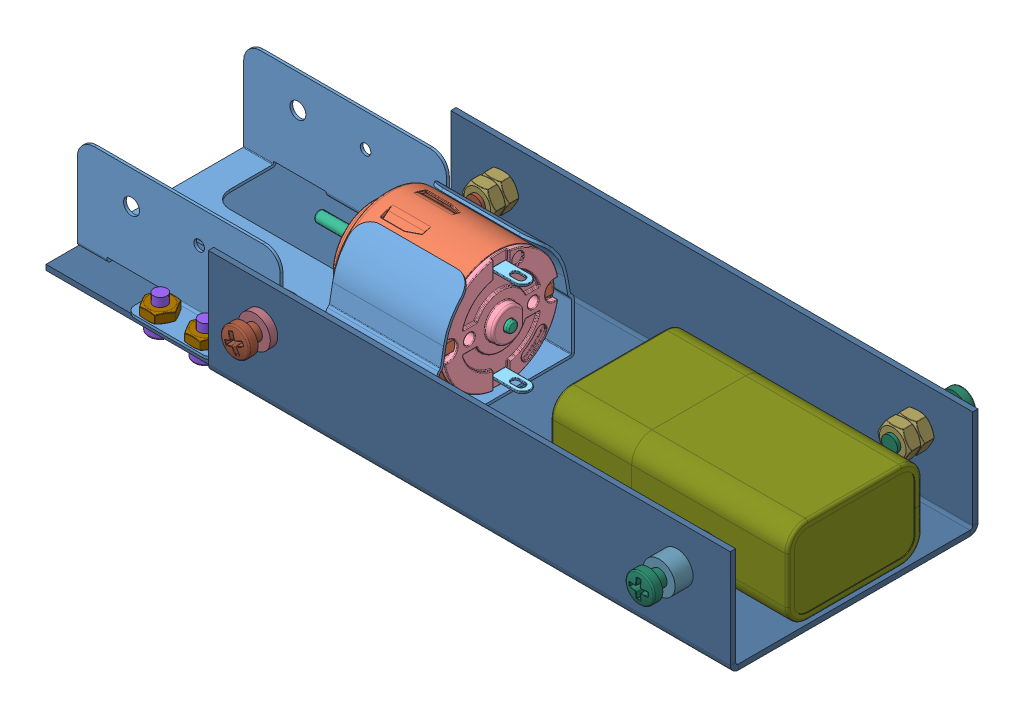
SolidWorks assembly Walking_robot_(fixed_body), configuration Default. Lengths in mm.
Overall size (130 25.8 61.22).
37 component instances, 16 part files, 0 mates.
Components (placement in the parent):
- ELENCO GEAR BOX 01-1: ELENCO GEAR BOX 01 [Default] at origin size (64.7 22.22 44.45)
- ELENCO DC Motor 3V-1: ELENCO DC Motor 3V [Predeterminado] at (28.3843 11.811 0) x (0 0 1) z (-1 0 0) size (22.78 22.72 39.63)
  - ELENCO MOTOR HOUSING 01-1: ELENCO MOTOR HOUSING 01 [Predeterminado] at (0 0 24.0663) size (21.61 21.6 25.37)
  - ELENCO FRONT BUSHING-1: ELENCO FRONT BUSHING [Predeterminado] at (0 0 28.0103) x (0.939098 -0.34365 0) z (0 0 1) size (4.5 4.5 0.5)
  - ELENCO MOTOR BACK 01-1: ELENCO MOTOR BACK 01 [Predeterminado] at (0 0 4.731) x (-1 0 0) z (0 0 -1) size (21.23 21.59 3.58)
  - Terminal3V-1: Terminal3V [Predeterminado] at (0 -8.7 5.331) x (1 0 0) z (0 1 0) size (2.9 8 0.4)
  - Terminal3V-2: Terminal3V [Predeterminado] at (0 8.7 5.331) x (1 0 0) z (0 1 0) size (2.9 8 0.4)
  - ELENCO ARMATURE 01-1: ELENCO ARMATURE 01 [Predeterminado] at (0 0 36.9603) x (-0.892263 0.451515 0) z (0 0 1) size (17 16.86 36.46)
  - Enrolamento3V-1: Enrolamento3V [Predeterminado] at (2.0691 4.0889 14.4603) x (0.892263 -0.451515 0) z (0 0 1) size (7 3 16)
  - Enrolamento3V-2: Enrolamento3V [Predeterminado] at (-4.5756 -0.2525 14.4603) x (-0.055108 0.99848 0) z (0 0 1) size (7 3 16)
  - Enrolamento3V-3: Enrolamento3V [Predeterminado] at (2.5065 -3.8363 14.4603) x (-0.837155 -0.546965 0) z (0 0 1) size (7 3 16)
- Walking_robot_(bolt_2_5x5)-1: Walking_robot_(bolt_2_5x5) [Default] at (-18.85 -1 19.55) x (0 -1 0) z (-0.551694 0 0.834047) size (6.57 4.4 4.4)
- Walking_robot_(nut_2_5)-1: Walking_robot_(nut_2_5) [Default] at (-18.85 2.368 19.55) x (0.999996 0 -0.002907) z (0 -1 0) size (5.74 5.33 2.2)
- Walking_robot_(bolt_2_5x5)-2: Walking_robot_(bolt_2_5x5) [Default] at (-18.85 -1 -19.55) x (0 -1 0) z (-0.551694 0 0.834047) size (6.57 4.4 4.4)
- Walking_robot_(bolt_2_5x5)-3: Walking_robot_(bolt_2_5x5) [Default] at (-10.35 -1 19.55) x (0 -1 0) z (-0.551694 0 0.834047) size (6.57 4.4 4.4)
- Walking_robot_(bolt_2_5x5)-4: Walking_robot_(bolt_2_5x5) [Default] at (-10.35 -1 -19.55) x (0 -1 0) z (-0.551694 0 0.834047) size (6.57 4.4 4.4)
- Walking_robot_(nut_2_5)-2: Walking_robot_(nut_2_5) [Default] at (-18.85 2.368 -19.55) x (0.999996 0 -0.002907) z (0 -1 0) size (5.74 5.33 2.2)
- Walking_robot_(nut_2_5)-3: Walking_robot_(nut_2_5) [Default] at (-10.35 2.368 19.55) x (0.999996 0 -0.002907) z (0 -1 0) size (5.74 5.33 2.2)
- Walking_robot_(nut_2_5)-4: Walking_robot_(nut_2_5) [Default] at (-10.35 2.368 -19.55) x (0.999996 0 -0.002907) z (0 -1 0) size (5.74 5.33 2.2)
- Walking_robot_(main_body)-1: Walking_robot_(main_body) [Default] at (42.9 -1 0) x (0 0 1) z (-1 0 0) size (46.5 20 130)
- Walking_robot_(bolt_3x10)-1: Walking_robot_(bolt_3x10) [Default] at (3.9 11.5 -26.63) x (0 0 -1) z (1 0 0) size (11.98 5.4 5.4)
- Walking_robot_(nut_3)-1: Walking_robot_(nut_3) [Default] at (3.9 11.5 -19.75) size (6.75 5.87 2.78)
- Walking_robot_(bolt_3x10)-2: Walking_robot_(bolt_3x10) [Default] at (3.9 11.5 26.63) x (0 0 1) z (-0.923728 -0.383049 0) size (11.98 5.4 5.4)
- Walking_robot_(nut_3)-7: Walking_robot_(nut_3) [Default] at (3.9 11.5 -22.25) size (6.75 5.87 2.78)
- Walking_robot_(nut_3)-9: Walking_robot_(nut_3) [Default] at (3.9 11.5 19.75) size (6.75 5.87 2.78)
- Walking_robot_(nut_3)-11: Walking_robot_(nut_3) [Default] at (3.9 11.5 17.25) size (6.75 5.87 2.78)
- Walking_robot_(spacer1)-1: Walking_robot_(spacer1) [Default] at (3.9 11.5 23.25) size (6 6 1.38)
- Walking_robot_(spacer1)-2: Walking_robot_(spacer1) [Default] at (3.9 11.5 -24.63) size (6 6 1.38)
- Walking_robot_(spacer2)-1: Walking_robot_(spacer2) [Default] at (81.9 11.5 23.25) size (6 6 3.38)
- Walking_robot_(spacer2)-2: Walking_robot_(spacer2) [Default] at (81.9 11.5 -26.63) size (6 6 3.38)
- Walking_robot_(bolt_3x12)-2: Walking_robot_(bolt_3x12) [Default] at (81.9 11.5 28.634) x (0 0 1) z (-1 0 0) size (13.98 5.4 5.4)
- Walking_robot_(bolt_3x12)-3: Walking_robot_(bolt_3x12) [Default] at (81.9 11.5 -28.634) x (0 0 -1) z (0.923728 0.383049 0) size (13.98 5.4 5.4)
- Walking_robot_(nut_3)-8: Walking_robot_(nut_3) [Default] at (81.9 11.5 -22.25) size (6.75 5.87 2.78)
- Walking_robot_(nut_3)-6: Walking_robot_(nut_3) [Default] at (81.9 11.5 -19.75) size (6.75 5.87 2.78)
- Walking_robot_(nut_3)-12: Walking_robot_(nut_3) [Default] at (81.9 11.5 17.25) size (6.75 5.87 2.78)
- Walking_robot_(nut_3)-10: Walking_robot_(nut_3) [Default] at (81.9 11.5 19.75) size (6.75 5.87 2.78)
- PR2007 9 Volt Battery-1: PR2007 9 Volt Battery [Default] at (69.0962 8.1788 -0.6579) x (0 0 -1) z (0 1 0) size (25.25 47.81 16.41)
